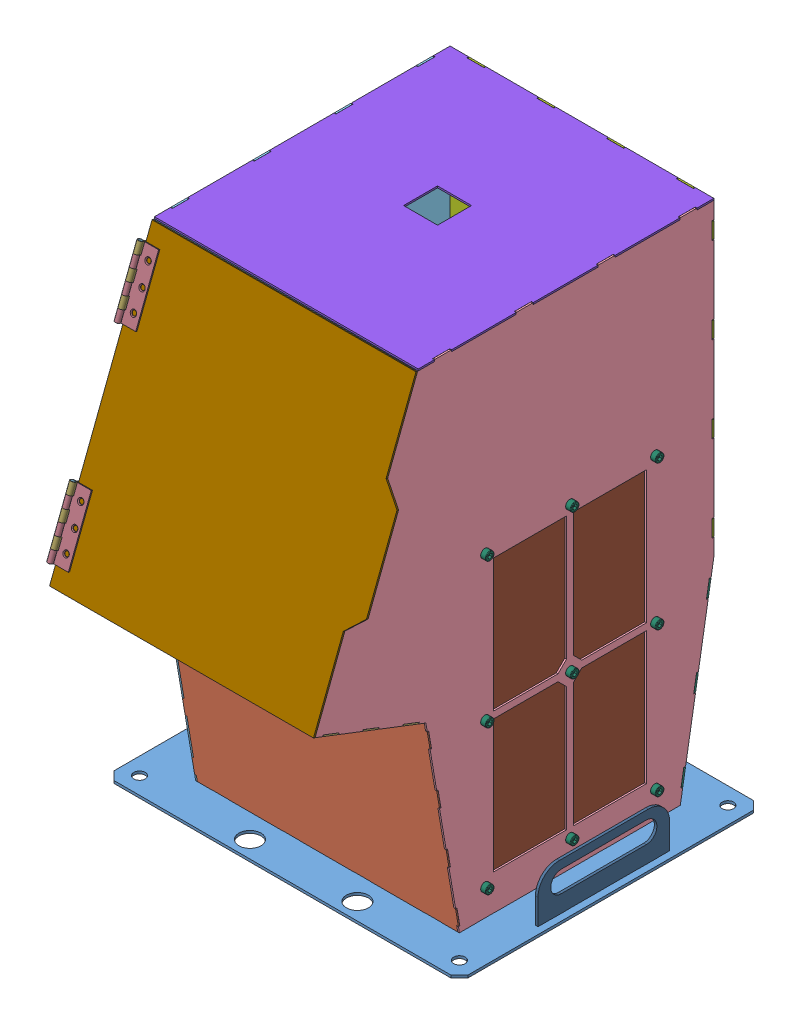
SolidWorks assembly SHRPRO-V1 1300.00-A Safety Hopper assembly, configuration Predeterminado. Lengths in mm.
Overall size (416.5 602 480.69).
47 component instances, 17 part files, 90 mates.
Components (placement in the parent):
- SHRPRO-V1 1300.01-A Hopper botton plate-2: SHRPRO-V1 1300.01-A Hopper botton plate [Predeterminado] at origin size (416.5 3 356)
- SHRPRO-V1 1300.02-A Hopper front plate 1-1: SHRPRO-V1 1300.02-A Hopper front plate 1 [Predeterminado] at (0 115.3216 149.4571) x (1 0 0) z (0 -0.986013 -0.166667) size (310.5 1.5 240)
- SHRPRO-V1 1300.03-A Hopper front plate 2-1: SHRPRO-V1 1300.03-A Hopper front plate 2 [Predeterminado] at (0 260.0362 233.7681) x (1 0 0) z (0 0.359616 0.9331) size (310.5 1.5 141)
- SHRPRO-V1 1300.04-A Hopper window side plate-1: SHRPRO-V1 1300.04-A Hopper window side plate [Predeterminado] at (155.25 297 -0.0429) x (0 0 -1) z (0 -1 0) size (469.63 2 602)
- SHRPRO-V1 1300.05-A Hopper side plate-2: SHRPRO-V1 1300.05-A Hopper side plate [Predeterminado] at (-153.25 297 -0.0429) x (0 0 -1) z (0 -1 0) size (469.63 2 602)
- SHRPRO-V1 1300.06-A Hopper back plate 1-1: SHRPRO-V1 1300.06-A Hopper back plate 1 [Predeterminado] at (0 115.6549 -147.5709) x (-1 0 0) z (0 0.986013 -0.166667) size (310.5 2 240)
- SHRPRO-V1 1300.07-A Hopper back plate 2-1: SHRPRO-V1 1300.07-A Hopper back plate 2 [Predeterminado] at (0 415.3216 -167.5429) x (-1 0 0) z (0 1 0) size (310.5 2 365.36)
- SHRPRO-V1 1300.08-A Hopper top plate-1: SHRPRO-V1 1300.08-A Hopper top plate [Predeterminado] at (0 599 4.4571) size (310.5 2 348)
- SHRPRO-V1 1300.09-A Hopper door plate-1: SHRPRO-V1 1300.09-A Hopper door plate [Predeterminado] at (0.4429 441.3383 241.9629) x (0.999998 -0.000803 -0.002083) z (0 -0.9331 0.359616) size (330 2 335.45)
- SHRPRO-V1 1300.10-A Hopper handle-1: SHRPRO-V1 1300.10-A Hopper handle [Predeterminado] at (192.25 27.5 0) x (0 0 -1) z (0 -1 0) size (155 3 58)
- SHRPRO-V1 1300.11-A Hopper window-1: SHRPRO-V1 1300.11-A Hopper window [Défaut] at (150.25 202 -0.0429) x (0 -1 0) z (0 0 1) size (360 3 220)
- SHRPRO-V1 Hinge-1: SHRPRO-V1 Hinge [Default] at (-158.25 580.3929 191.9661) x (0 0.9331 -0.359616) z (0 0.359616 0.9331) size (79.62 24.63 23.9) (flexible)
  - 52-1-3990_01 v2.2-1: 52-1-3990_01 v2.2 [Default] at origin size (75 6 23)
  - 52-1-3990_02 v2.2-1: 52-1-3990_02 v2.2 [Default] x (1 0 0) z (0 -0.999998 -0.002233) size (75 6 23)
  - 52-1-3990_03 v2.2-1: 52-1-3990_03 v2.2 [Default] x (1 0 0) z (0 -0.348451 0.937327) size (79.62 7.82 5.45)
- SHRPRO-V1 Hinge-2: SHRPRO-V1 Hinge [Default] at (-158.25 374.6838 271.2463) x (0 0.9331 -0.359616) z (0 0.359616 0.9331) size (79.62 24.63 23.9) (flexible)
  - 52-1-3990_01 v2.2-1: 52-1-3990_01 v2.2 [Default] at origin size (75 6 23)
  - 52-1-3990_02 v2.2-1: 52-1-3990_02 v2.2 [Default] x (1 0 0) z (0 -0.999998 -0.002233) size (75 6 23)
  - 52-1-3990_03 v2.2-1: 52-1-3990_03 v2.2 [Default] x (1 0 0) z (0 -0.348451 0.937327) size (79.62 7.82 5.45)
- SHRPRO-V1 1300.10-A Hopper handle-2: SHRPRO-V1 1300.10-A Hopper handle [Predeterminado] at (-192.25 27.5 0) x (0 0 1) z (0 -1 0) size (155 3 58)
- socket head cap screw_din-2: socket head cap screw_din [DIN 912 M6 x 12 --- 12N] at (161.25 372 -100.0429) x (-1 0 0) z (0 0.924225 0.381849) size (18 10 10)
- socket head cap screw_din-3: socket head cap screw_din [DIN 912 M6 x 12 --- 12N] at (161.25 372 -0.0429) x (-1 0 0) z (0 0.924225 0.381849) size (18 10 10)
- socket head cap screw_din-4: socket head cap screw_din [DIN 912 M6 x 12 --- 12N] at (161.25 372 99.9571) x (-1 0 0) z (0 0.924225 0.381849) size (18 10 10)
- socket head cap screw_din-5: socket head cap screw_din [DIN 912 M6 x 12 --- 12N] at (161.25 202 -0.0429) x (-1 0 0) z (0 0.924225 0.381849) size (18 10 10)
- socket head cap screw_din-6: socket head cap screw_din [DIN 912 M6 x 12 --- 12N] at (161.25 202 -100.0429) x (-1 0 0) z (0 0.924225 0.381849) size (18 10 10)
- socket head cap screw_din-7: socket head cap screw_din [DIN 912 M6 x 12 --- 12N] at (161.25 202 99.9571) x (-1 0 0) z (0 0.924225 0.381849) size (18 10 10)
- socket head cap screw_din-8: socket head cap screw_din [DIN 912 M6 x 12 --- 12N] at (161.25 32 99.9571) x (-1 0 0) z (0 0.924225 0.381849) size (18 10 10)
- socket head cap screw_din-9: socket head cap screw_din [DIN 912 M6 x 12 --- 12N] at (161.25 32 -0.0429) x (-1 0 0) z (0 0.924225 0.381849) size (18 10 10)
- socket head cap screw_din-10: socket head cap screw_din [DIN 912 M6 x 12 --- 12N] at (161.25 32 -100.0429) x (-1 0 0) z (0 0.924225 0.381849) size (18 10 10)
- hex nut gradec_din-1: hex nut gradec_din [Hexagon Nut ISO 4034 - M6 - N] at (142.55 32 -100.0429) x (0 0 1) z (-1 0 0) size (10 11.55 6.1)
- hex nut gradec_din-2: hex nut gradec_din [Hexagon Nut ISO 4034 - M6 - N] at (142.55 32 -0.0429) x (0 0 1) z (-1 0 0) size (10 11.55 6.1)
- hex nut gradec_din-3: hex nut gradec_din [Hexagon Nut ISO 4034 - M6 - N] at (142.55 202 -100.0429) x (0 0 1) z (-1 0 0) size (10 11.55 6.1)
- hex nut gradec_din-4: hex nut gradec_din [Hexagon Nut ISO 4034 - M6 - N] at (142.55 32 99.9571) x (0 0 1) z (-1 0 0) size (10 11.55 6.1)
- hex nut gradec_din-5: hex nut gradec_din [Hexagon Nut ISO 4034 - M6 - N] at (142.55 202 99.9571) x (0 0 1) z (-1 0 0) size (10 11.55 6.1)
- hex nut gradec_din-6: hex nut gradec_din [Hexagon Nut ISO 4034 - M6 - N] at (142.55 202 -0.0429) x (0 0 1) z (-1 0 0) size (10 11.55 6.1)
- hex nut gradec_din-7: hex nut gradec_din [Hexagon Nut ISO 4034 - M6 - N] at (142.55 372 -0.0429) x (0 0 1) z (-1 0 0) size (10 11.55 6.1)
- hex nut gradec_din-8: hex nut gradec_din [Hexagon Nut ISO 4034 - M6 - N] at (142.55 372 -100.0429) x (0 0 1) z (-1 0 0) size (10 11.55 6.1)
- hex nut gradec_din-9: hex nut gradec_din [Hexagon Nut ISO 4034 - M6 - N] at (142.55 372 99.9571) x (0 0 1) z (-1 0 0) size (10 11.55 6.1)
- plain washer normal grade c_iso-3: plain washer normal grade c_iso [Washer ISO 7091 - 6] at (150.25 372 -100.0429) size (1.6 12 12)
- plain washer normal grade c_iso-4: plain washer normal grade c_iso [Washer ISO 7091 - 6] at (150.25 372 -0.0429) size (1.6 12 12)
- plain washer normal grade c_iso-5: plain washer normal grade c_iso [Washer ISO 7091 - 6] at (150.25 372 99.9571) size (1.6 12 12)
- plain washer normal grade c_iso-6: plain washer normal grade c_iso [Washer ISO 7091 - 6] at (150.25 202 -100.0429) size (1.6 12 12)
- plain washer normal grade c_iso-7: plain washer normal grade c_iso [Washer ISO 7091 - 6] at (150.25 202 -0.0429) size (1.6 12 12)
- plain washer normal grade c_iso-8: plain washer normal grade c_iso [Washer ISO 7091 - 6] at (150.25 202 99.9571) size (1.6 12 12)
- plain washer normal grade c_iso-9: plain washer normal grade c_iso [Washer ISO 7091 - 6] at (150.25 32 -100.0429) size (1.6 12 12)
- plain washer normal grade c_iso-10: plain washer normal grade c_iso [Washer ISO 7091 - 6] at (150.25 32 -0.0429) x (1 0 0) z (0 0.799121 0.60117) size (1.6 12 12)
- plain washer normal grade c_iso-11: plain washer normal grade c_iso [Washer ISO 7091 - 6] at (150.25 32 99.9571) size (1.6 12 12)
Mates (geometry in assembly coordinates):
- Coordinate2: coordinate: point of SHRPRO-V1 1300.01-A Hopper botton plate-2; point of assembly
- Coincident51: coincident: plane of SHRPRO-V1 1300.01-A Hopper botton plate-2 through (155.25 -3 130.05) normal (-1 0 0); plane of SHRPRO-V1 1300.04-A Hopper window side plate-1 through (155.25 297 -0.0429) normal (1 0 0)
- Coincident52: coincident: plane of SHRPRO-V1 1300.01-A Hopper botton plate-2 through (0 -3 0) normal (0 -1 0); plane of SHRPRO-V1 1300.04-A Hopper window side plate-1 through (153.25 -3 129.4571) normal (0 -1 0)
- Coincident53: coincident: plane of SHRPRO-V1 1300.04-A Hopper window side plate-1 through (155.25 297 -0.0429) normal (1 0 0); plane of SHRPRO-V1 1300.08-A Hopper top plate-1 through (155.25 597 178.4571) normal (1 0 0)
- Coincident54: coincident: plane of SHRPRO-V1 1300.04-A Hopper window side plate-1 through (153.25 597 -169.5429) normal (0 1 0); plane of SHRPRO-V1 1300.08-A Hopper top plate-1 through (0 597 4.4571) normal (0 -1 0)
- Coincident55: coincident: plane of SHRPRO-V1 1300.04-A Hopper window side plate-1 through (153.25 233.6432 -169.5429) normal (0 0 -1); plane of SHRPRO-V1 1300.08-A Hopper top plate-1 through (-155.25 597 -169.5429) normal (0 0 -1)
- Coincident56: coincident: plane of SHRPRO-V1 1300.08-A Hopper top plate-1 through (0 597 4.4571) normal (0 -1 0); plane of SHRPRO-V1 1300.05-A Hopper side plate-2 through (-155.25 597 -169.5429) normal (0 1 0)
- Coincident57: coincident: plane of SHRPRO-V1 1300.08-A Hopper top plate-1 through (-155.25 597 -169.5429) normal (0 0 -1); plane of SHRPRO-V1 1300.05-A Hopper side plate-2 through (-155.25 233.6432 -169.5429) normal (0 0 -1)
- Coincident58: coincident: plane of SHRPRO-V1 1300.08-A Hopper top plate-1 through (-155.25 597 178.4571) normal (-1 0 0); plane of SHRPRO-V1 1300.05-A Hopper side plate-2 through (-155.25 297 -0.0429) normal (-1 0 0)
- Coincident59: coincident: plane of SHRPRO-V1 1300.07-A Hopper back plate 2-1 through (0 415.3216 -169.5429) normal (0 0 -1); plane of SHRPRO-V1 1300.05-A Hopper side plate-2 through (-155.25 233.6432 -169.5429) normal (0 0 -1)
- Coincident60: coincident: plane of SHRPRO-V1 1300.07-A Hopper back plate 2-1 through (153.25 597 -169.5429) normal (0 1 0); plane of SHRPRO-V1 1300.08-A Hopper top plate-1 through (0 597 4.4571) normal (0 -1 0)
- Coincident61: coincident: plane of SHRPRO-V1 1300.07-A Hopper back plate 2-1 through (153.25 597 -169.5429) normal (1 0 0); plane of SHRPRO-V1 1300.04-A Hopper window side plate-1 through (153.25 297 -0.0429) normal (-1 0 0)
- Coincident63: coincident: plane of SHRPRO-V1 1300.04-A Hopper window side plate-1 through (153.25 297 -0.0429) normal (-1 0 0); plane of SHRPRO-V1 1300.03-A Hopper front plate 2-1 through (153.25 283.9895 300.0911) normal (1 0 0)
- Coincident64: coincident: plane of SHRPRO-V1 1300.04-A Hopper window side plate-1 through (153.25 233.6432 169.4571) normal (0 -0.9331 0.359616); plane of SHRPRO-V1 1300.03-A Hopper front plate 2-1 through (0 258.6365 234.3076) normal (0 -0.9331 0.359616)
- Coincident66: coincident: plane of SHRPRO-V1 1300.02-A Hopper front plate 1-1 through (0 115.3216 149.4571) normal (0 -0.166667 0.986013); plane of SHRPRO-V1 1300.04-A Hopper window side plate-1 through (153.25 233.6432 169.4571) normal (0 -0.166667 0.986013)
- Coincident67: coincident: line of SHRPRO-V1 1300.01-A Hopper botton plate-2 through (155.25 0 -130.05) axis (-1 0 0); plane of SHRPRO-V1 1300.04-A Hopper window side plate-1 through (153.25 -3 -129.5429) normal (0 -0.166667 -0.986013)
- Coincident68: coincident: plane of SHRPRO-V1 1300.02-A Hopper front plate 1-1 through (153.25 -2.75 127.9781) normal (1 0 0); plane of SHRPRO-V1 1300.04-A Hopper window side plate-1 through (153.25 297 -0.0429) normal (-1 0 0)
- Coincident70: coincident: plane of SHRPRO-V1 1300.04-A Hopper window side plate-1 through (153.25 297 -0.0429) normal (-1 0 0); plane of SHRPRO-V1 1300.06-A Hopper back plate 1-1 through (153.25 233.6432 -169.5429) normal (1 0 0)
- Coincident71: coincident: plane of SHRPRO-V1 1300.04-A Hopper window side plate-1 through (153.25 -3 -129.5429) normal (0 -0.166667 -0.986013); plane of SHRPRO-V1 1300.06-A Hopper back plate 1-1 through (0 115.3216 -149.5429) normal (0 -0.166667 -0.986013)
- Coincident73: coincident: plane of SHRPRO-V1 1300.01-A Hopper botton plate-2 through (0 -3 0) normal (0 -1 0); line of SHRPRO-V1 1300.06-A Hopper back plate 1-1 through (-153.25 -3 -129.5429) axis (1 0 0)
- Coincident75: coincident: plane of SHRPRO-V1 1300.01-A Hopper botton plate-2 through (0 -3 0) normal (0 -1 0); line of SHRPRO-V1 1300.02-A Hopper front plate 1-1 through (-153.25 -3 129.4571) axis (1 0 0)
- Coincident78: coincident: line of SHRPRO-V1 1300.04-A Hopper window side plate-1 through (153.25 283.9895 300.0911) axis (1 0 0); line of SHRPRO-V1 1300.03-A Hopper front plate 2-1 through (-153.25 283.9895 300.0911) axis (1 0 0)
- Coincident81: coincident: plane of SHRPRO-V1 1300.05-A Hopper side plate-2 through (-155.25 297 -0.0429) normal (-1 0 0); plane of SHRPRO-V1 Hinge-1/52-1-3990_01 v2.2-1 through (-155.25 580.3929 191.9661) normal (1 0 0)
- Coincident82: coincident: plane of SHRPRO-V1 1300.09-A Hopper door plate-1 through (0.4429 441.3383 241.9629) normal (0.002233 0.359615 0.933098); plane of SHRPRO-V1 Hinge-1/52-1-3990_02 v2.2-1 through (-158.2567 509.3315 216.138) normal (-0.002233 -0.359615 -0.933098)
- Coincident83: coincident: plane of SHRPRO-V1 1300.05-A Hopper side plate-2 through (-155.25 233.6432 169.4571) normal (0 -0.9331 0.359616); point of SHRPRO-V1 1300.09-A Hopper door plate-1
- Distance3: distance = 2 mm: plane of SHRPRO-V1 Hinge-1/52-1-3990_01 v2.2-1 through (-155.25 555.7348 197.5041) normal (0 0.359616 0.9331); plane of SHRPRO-V1 1300.05-A Hopper side plate-2 through (-155.25 283.9895 300.0911) normal (0 0.359616 0.9331)
- Distance2: coincident: plane of SHRPRO-V1 1300.09-A Hopper door plate-1 through (-154.5612 284.2382 300.7366) normal (-0.999998 0.000803 0.002083); plane of SHRPRO-V1 Hinge-1/52-1-3990_02 v2.2-1 through (-154.5567 579.3111 189.1591) normal (-0.999998 0.000803 0.002083)
- Distance4: distance = 20 mm: plane of SHRPRO-V1 Hinge-2/52-1-3990_01 v2.2-1 through (-156.8928 302.3746 292.1805) normal (0 -0.9331 0.359616); plane of SHRPRO-V1 1300.05-A Hopper side plate-2 through (-155.25 233.6432 169.4571) normal (0 -0.9331 0.359616)
- Coincident86: coincident: plane of SHRPRO-V1 1300.09-A Hopper door plate-1 through (0.4429 441.3383 241.9629) normal (0.002233 0.359615 0.933098); plane of SHRPRO-V1 Hinge-2/52-1-3990_02 v2.2-1 through (-158.2567 303.6224 295.4182) normal (-0.002233 -0.359615 -0.933098)
- Concentric1: concentric: cylinder of SHRPRO-V1 1300.04-A Hopper window side plate-1 through (155.25 372 99.9571) axis (1 0 0) radius 3.3; cylinder of SHRPRO-V1 1300.11-A Hopper window-1 through (150.25 372 99.9571) axis (-1 0 0) radius 3.3
- Concentric2: concentric: cylinder of SHRPRO-V1 1300.04-A Hopper window side plate-1 through (155.25 32 -100.0429) axis (1 0 0) radius 3.3; cylinder of SHRPRO-V1 1300.11-A Hopper window-1 through (150.25 32 -100.0429) axis (-1 0 0) radius 3.3
- Coincident88: coincident: plane of SHRPRO-V1 1300.01-A Hopper botton plate-2 through (0 0 0) normal (0 1 0); plane of SHRPRO-V1 1300.10-A Hopper handle-1 through (195.25 0 77.5) normal (0 -1 0)
- Distance5: distance = 8 mm: plane of SHRPRO-V1 1300.10-A Hopper handle-1 through (195.25 27.5 0) normal (1 0 0); plane of SHRPRO-V1 1300.01-A Hopper botton plate-2 through (203.25 -3 178) normal (1 0 0)
- Coincident89: coincident: plane of SHRPRO-V1 1300.01-A Hopper botton plate-2 through (0 0 0) normal (0 0 1); plane of SHRPRO-V1 1300.10-A Hopper handle-1 through (192.25 27.5 0) normal (0 0 -1)
- Coincident90: coincident: line of SHRPRO-V1 1300.04-A Hopper window side plate-1 through (155.25 597 179.4571) axis (0 -0.9331 0.359616); plane of SHRPRO-V1 1300.09-A Hopper door plate-1 through (0.4384 440.619 240.0967) normal (-0.002233 -0.359615 -0.933098)
- Concentric4: concentric: cylinder of SHRPRO-V1 1300.11-A Hopper window-1 through (150.25 372 -100.0429) axis (-1 0 0) radius 3.3; cylinder of socket head cap screw_din-2 through (193 372 -100.0429) axis (1 0 0) radius 5
- Coincident92: coincident: plane of SHRPRO-V1 1300.04-A Hopper window side plate-1 through (155.25 297 -0.0429) normal (1 0 0); plane of socket head cap screw_din-2 through (155.25 370.0908 -95.4218) normal (-1 0 0)
- Concentric5: concentric: cylinder of SHRPRO-V1 1300.11-A Hopper window-1 through (150.25 372 -0.0429) axis (-1 0 0) radius 3.3; cylinder of socket head cap screw_din-3 through (193 372 -0.0429) axis (1 0 0) radius 5
- Coincident93: coincident: plane of SHRPRO-V1 1300.04-A Hopper window side plate-1 through (155.25 297 -0.0429) normal (1 0 0); plane of socket head cap screw_din-3 through (155.25 370.0908 4.5782) normal (-1 0 0)
- Concentric6: concentric: cylinder of SHRPRO-V1 1300.11-A Hopper window-1 through (150.25 372 99.9571) axis (-1 0 0) radius 3.3; cylinder of socket head cap screw_din-4 through (193 372 99.9571) axis (1 0 0) radius 5
- Coincident94: coincident: plane of SHRPRO-V1 1300.04-A Hopper window side plate-1 through (155.25 297 -0.0429) normal (1 0 0); plane of socket head cap screw_din-4 through (155.25 370.0908 104.5782) normal (-1 0 0)
- Concentric7: concentric: cylinder of SHRPRO-V1 1300.11-A Hopper window-1 through (150.25 202 -0.0429) axis (-1 0 0) radius 3.3; cylinder of socket head cap screw_din-5 through (193 202 -0.0429) axis (1 0 0) radius 5
- Coincident95: coincident: plane of SHRPRO-V1 1300.04-A Hopper window side plate-1 through (155.25 297 -0.0429) normal (1 0 0); plane of socket head cap screw_din-5 through (155.25 200.0908 4.5782) normal (-1 0 0)
- Concentric8: concentric: cylinder of SHRPRO-V1 1300.11-A Hopper window-1 through (150.25 202 -100.0429) axis (-1 0 0) radius 3.3; cylinder of socket head cap screw_din-6 through (193 202 -100.0429) axis (1 0 0) radius 5
- Coincident96: coincident: plane of SHRPRO-V1 1300.04-A Hopper window side plate-1 through (155.25 297 -0.0429) normal (1 0 0); plane of socket head cap screw_din-6 through (155.25 200.0908 -95.4218) normal (-1 0 0)
- Concentric9: concentric: cylinder of SHRPRO-V1 1300.11-A Hopper window-1 through (150.25 202 99.9571) axis (-1 0 0) radius 3.3; cylinder of socket head cap screw_din-7 through (193 202 99.9571) axis (1 0 0) radius 5
- Coincident97: coincident: plane of SHRPRO-V1 1300.04-A Hopper window side plate-1 through (155.25 297 -0.0429) normal (1 0 0); plane of socket head cap screw_din-7 through (155.25 200.0908 104.5782) normal (-1 0 0)
- Concentric10: concentric: cylinder of SHRPRO-V1 1300.11-A Hopper window-1 through (150.25 32 99.9571) axis (-1 0 0) radius 3.3; cylinder of socket head cap screw_din-8 through (193 32 99.9571) axis (1 0 0) radius 5
- Coincident98: coincident: plane of SHRPRO-V1 1300.04-A Hopper window side plate-1 through (155.25 297 -0.0429) normal (1 0 0); plane of socket head cap screw_din-8 through (155.25 30.0908 104.5782) normal (-1 0 0)
- Concentric11: concentric: cylinder of SHRPRO-V1 1300.11-A Hopper window-1 through (150.25 32 -0.0429) axis (-1 0 0) radius 3.3; cylinder of socket head cap screw_din-9 through (193 32 -0.0429) axis (1 0 0) radius 5
- Coincident99: coincident: plane of SHRPRO-V1 1300.04-A Hopper window side plate-1 through (155.25 297 -0.0429) normal (1 0 0); plane of socket head cap screw_din-9 through (155.25 30.0908 4.5782) normal (-1 0 0)
- Concentric12: concentric: cylinder of SHRPRO-V1 1300.11-A Hopper window-1 through (150.25 32 -100.0429) axis (-1 0 0) radius 3.3; cylinder of socket head cap screw_din-10 through (193 32 -100.0429) axis (1 0 0) radius 5
- Coincident100: coincident: plane of SHRPRO-V1 1300.04-A Hopper window side plate-1 through (155.25 297 -0.0429) normal (1 0 0); plane of socket head cap screw_din-10 through (155.25 30.0908 -95.4218) normal (-1 0 0)
- Concentric13: concentric: cylinder of SHRPRO-V1 1300.04-A Hopper window side plate-1 through (155.25 32 -100.0429) axis (1 0 0) radius 3.3; cylinder of hex nut gradec_din-1 through (167.5875 32 -100.0429) axis (-1 0 0) radius 3
- Coincident101: coincident: plane of plain washer normal grade c_iso-9 through (148.65 38 -100.0429) normal (-1 0 0); plane of hex nut gradec_din-1 through (148.65 37.7735 -100.0429) normal (1 0 0)
- Concentric14: concentric: cylinder of SHRPRO-V1 1300.04-A Hopper window side plate-1 through (155.25 32 -0.0429) axis (1 0 0) radius 3.3; cylinder of hex nut gradec_din-2 through (167.5875 32 -0.0429) axis (-1 0 0) radius 3
- Coincident102: coincident: plane of plain washer normal grade c_iso-10 through (148.65 35.607 -4.8376) normal (-1 0 0); plane of hex nut gradec_din-2 through (148.65 37.7735 -0.0429) normal (1 0 0)
- Concentric15: concentric: cylinder of SHRPRO-V1 1300.04-A Hopper window side plate-1 through (155.25 202 -100.0429) axis (1 0 0) radius 3.3; cylinder of hex nut gradec_din-3 through (167.5875 202 -100.0429) axis (-1 0 0) radius 3
- Coincident103: coincident: plane of plain washer normal grade c_iso-6 through (148.65 208 -100.0429) normal (-1 0 0); plane of hex nut gradec_din-3 through (148.65 207.7735 -100.0429) normal (1 0 0)
- Concentric16: concentric: cylinder of SHRPRO-V1 1300.04-A Hopper window side plate-1 through (155.25 32 99.9571) axis (1 0 0) radius 3.3; cylinder of hex nut gradec_din-4 through (167.5875 32 99.9571) axis (-1 0 0) radius 3
- Coincident104: coincident: plane of plain washer normal grade c_iso-11 through (148.65 38 99.9571) normal (-1 0 0); plane of hex nut gradec_din-4 through (148.65 37.7735 99.9571) normal (1 0 0)
- Concentric17: concentric: cylinder of SHRPRO-V1 1300.04-A Hopper window side plate-1 through (155.25 202 99.9571) axis (1 0 0) radius 3.3; cylinder of hex nut gradec_din-5 through (167.5875 202 99.9571) axis (-1 0 0) radius 3
- Coincident105: coincident: plane of plain washer normal grade c_iso-8 through (148.65 208 99.9571) normal (-1 0 0); plane of hex nut gradec_din-5 through (148.65 207.7735 99.9571) normal (1 0 0)
- Concentric18: concentric: cylinder of SHRPRO-V1 1300.04-A Hopper window side plate-1 through (155.25 202 -0.0429) axis (1 0 0) radius 3.3; cylinder of hex nut gradec_din-6 through (167.5875 202 -0.0429) axis (-1 0 0) radius 3
- Coincident106: coincident: plane of plain washer normal grade c_iso-7 through (148.65 208 -0.0429) normal (-1 0 0); plane of hex nut gradec_din-6 through (148.65 207.7735 -0.0429) normal (1 0 0)
- Concentric19: concentric: cylinder of SHRPRO-V1 1300.04-A Hopper window side plate-1 through (155.25 372 -0.0429) axis (1 0 0) radius 3.3; cylinder of hex nut gradec_din-7 through (167.5875 372 -0.0429) axis (-1 0 0) radius 3
- Coincident107: coincident: plane of plain washer normal grade c_iso-4 through (148.65 378 -0.0429) normal (-1 0 0); plane of hex nut gradec_din-7 through (148.65 377.7735 -0.0429) normal (1 0 0)
- Concentric20: concentric: cylinder of SHRPRO-V1 1300.04-A Hopper window side plate-1 through (155.25 372 -100.0429) axis (1 0 0) radius 3.3; cylinder of hex nut gradec_din-8 through (167.5875 372 -100.0429) axis (-1 0 0) radius 3
- Coincident108: coincident: plane of plain washer normal grade c_iso-3 through (148.65 378 -100.0429) normal (-1 0 0); plane of hex nut gradec_din-8 through (148.65 377.7735 -100.0429) normal (1 0 0)
- Concentric21: concentric: cylinder of SHRPRO-V1 1300.04-A Hopper window side plate-1 through (155.25 372 99.9571) axis (1 0 0) radius 3.3; cylinder of hex nut gradec_din-9 through (167.5875 372 99.9571) axis (-1 0 0) radius 3
- Coincident109: coincident: plane of plain washer normal grade c_iso-5 through (148.65 378 99.9571) normal (-1 0 0); plane of hex nut gradec_din-9 through (148.65 377.7735 99.9571) normal (1 0 0)
- Concentric22: concentric: cylinder of SHRPRO-V1 1300.11-A Hopper window-1 through (150.25 372 -100.0429) axis (-1 0 0) radius 3.3; cylinder of plain washer normal grade c_iso-3 through (115.325 372 -100.0429) axis (-1 0 0) radius 3.3
- Coincident110: coincident: plane of SHRPRO-V1 1300.11-A Hopper window-1 through (150.25 202 -0.0429) normal (-1 0 0); plane of plain washer normal grade c_iso-3 through (150.25 375.3 -100.0429) normal (1 0 0)
- Concentric23: concentric: cylinder of SHRPRO-V1 1300.11-A Hopper window-1 through (150.25 372 -0.0429) axis (-1 0 0) radius 3.3; cylinder of plain washer normal grade c_iso-4 through (115.325 372 -0.0429) axis (-1 0 0) radius 3.3
- Coincident111: coincident: plane of SHRPRO-V1 1300.11-A Hopper window-1 through (150.25 202 -0.0429) normal (-1 0 0); plane of plain washer normal grade c_iso-4 through (150.25 375.3 -0.0429) normal (1 0 0)
- Concentric24: concentric: cylinder of SHRPRO-V1 1300.11-A Hopper window-1 through (150.25 372 99.9571) axis (-1 0 0) radius 3.3; cylinder of plain washer normal grade c_iso-5 through (115.325 372 99.9571) axis (-1 0 0) radius 3.3
- Coincident112: coincident: plane of SHRPRO-V1 1300.11-A Hopper window-1 through (150.25 202 -0.0429) normal (-1 0 0); plane of plain washer normal grade c_iso-5 through (150.25 375.3 99.9571) normal (1 0 0)
- Concentric25: concentric: cylinder of SHRPRO-V1 1300.11-A Hopper window-1 through (150.25 202 -100.0429) axis (-1 0 0) radius 3.3; cylinder of plain washer normal grade c_iso-6 through (115.325 202 -100.0429) axis (-1 0 0) radius 3.3
- Coincident113: coincident: plane of SHRPRO-V1 1300.11-A Hopper window-1 through (150.25 202 -0.0429) normal (-1 0 0); plane of plain washer normal grade c_iso-6 through (150.25 205.3 -100.0429) normal (1 0 0)
- Concentric26: concentric: cylinder of SHRPRO-V1 1300.11-A Hopper window-1 through (150.25 202 -0.0429) axis (-1 0 0) radius 3.3; cylinder of plain washer normal grade c_iso-7 through (115.325 202 -0.0429) axis (-1 0 0) radius 3.3
- Coincident114: coincident: plane of SHRPRO-V1 1300.11-A Hopper window-1 through (150.25 202 -0.0429) normal (-1 0 0); plane of plain washer normal grade c_iso-7 through (150.25 205.3 -0.0429) normal (1 0 0)
- Concentric27: concentric: cylinder of SHRPRO-V1 1300.11-A Hopper window-1 through (150.25 202 99.9571) axis (-1 0 0) radius 3.3; cylinder of plain washer normal grade c_iso-8 through (115.325 202 99.9571) axis (-1 0 0) radius 3.3
- Coincident115: coincident: plane of SHRPRO-V1 1300.11-A Hopper window-1 through (150.25 202 -0.0429) normal (-1 0 0); plane of plain washer normal grade c_iso-8 through (150.25 205.3 99.9571) normal (1 0 0)
- Concentric28: concentric: cylinder of SHRPRO-V1 1300.11-A Hopper window-1 through (150.25 32 -100.0429) axis (-1 0 0) radius 3.3; cylinder of plain washer normal grade c_iso-9 through (115.325 32 -100.0429) axis (-1 0 0) radius 3.3
- Coincident116: coincident: plane of SHRPRO-V1 1300.11-A Hopper window-1 through (150.25 202 -0.0429) normal (-1 0 0); plane of plain washer normal grade c_iso-9 through (150.25 35.3 -100.0429) normal (1 0 0)
- Concentric29: concentric: cylinder of SHRPRO-V1 1300.11-A Hopper window-1 through (150.25 32 -0.0429) axis (-1 0 0) radius 3.3; cylinder of plain washer normal grade c_iso-10 through (115.325 32 -0.0429) axis (-1 0 0) radius 3.3
- Concentric30: concentric: cylinder of SHRPRO-V1 1300.11-A Hopper window-1 through (150.25 32 99.9571) axis (-1 0 0) radius 3.3; cylinder of plain washer normal grade c_iso-11 through (115.325 32 99.9571) axis (-1 0 0) radius 3.3
- Coincident117: coincident: plane of SHRPRO-V1 1300.11-A Hopper window-1 through (150.25 202 -0.0429) normal (-1 0 0); plane of plain washer normal grade c_iso-11 through (150.25 35.3 99.9571) normal (1 0 0)
- Coincident118: coincident: plane of SHRPRO-V1 1300.04-A Hopper window side plate-1 through (153.25 297 -0.0429) normal (-1 0 0); plane of SHRPRO-V1 1300.11-A Hopper window-1 through (153.25 202 -0.0429) normal (1 0 0)
- Coincident119: coincident: plane of SHRPRO-V1 1300.11-A Hopper window-1 through (150.25 202 -0.0429) normal (-1 0 0); plane of plain washer normal grade c_iso-10 through (150.25 33.9839 -2.68) normal (1 0 0)
